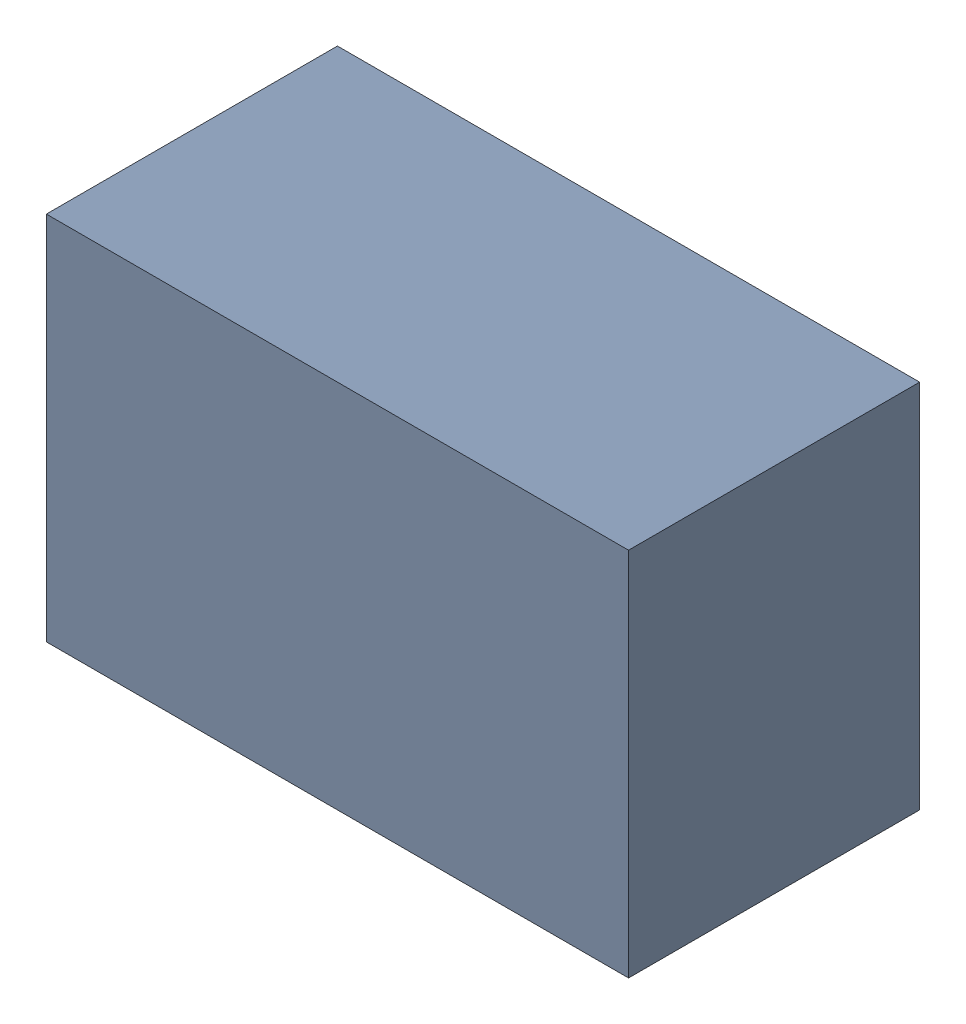
SolidWorks assembly D8, configuration Default. Lengths in mm.
Overall size (1.1 0.7 0.55).
2 component instances, 1 part files, 0 mates.
Components (placement in the parent):
- 870944480-1: 870944480 [Default] at (76.885 41.857 0) size (1.1 0.7 0.55)
  - Extruded_32-1: Extruded_32 [Default] at origin size (1.1 0.7 0.55)
